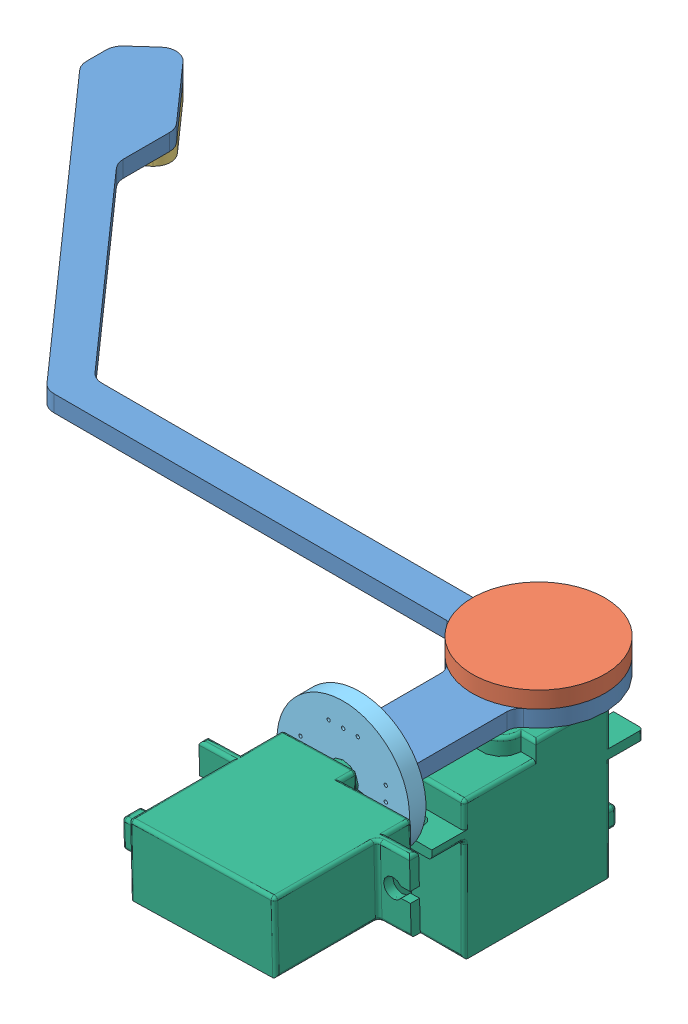
SolidWorks assembly Record Needle Main, configuration Default. Lengths in mm.
Overall size (169.13 48.12 136.87).
8 component instances, 7 part files, 10 mates.
Components (placement in the parent):
- Needle Arm-1: Needle Arm [Default] at origin size (154.66 3.17 103.67)
- X-Y Turn Top-1: X-Y Turn Top [Default] at origin size (25.4 3.17 25.4)
- Needle Bottom-1: Needle Bottom [Default] at origin size (18.51 3.17 20.89)
- Needle Point-1: Needle Point [Default] at (-130.291 -3.175 -53.8527) x (-0.670402 0 -0.741998) z (0 1 0) size (6.35 3.17 9.52)
- X-Z Servo Mount-1: X-Z Servo Mount [Default] at (0 1.5875 37.465) x (0 -1 0) z (1 0 0) size (25.4 3.17 25.4)
- Part4^Record Needle Main-1: Part4^Record Needle Main [Default] at origin (virtual)
- HK15148 Servo-1: HK15148 Servo [Default] at (-6.724 -33.8328 20.774) x (0.999994 0 0.003328) z (-0.003328 0 0.999994) size (13.31 33.83 40.39)
- HK15148 Servo-3: HK15148 Servo [Default] at (20.6314 8.7369 71.2978) x (0.023875 -0.999715 0) z (0.999715 0.023875 0) size (13.31 33.83 40.39)
Mates (geometry in assembly coordinates):
- Coincident3: coincident: line of Needle Bottom-1 through (-134.5481 -3.175 -58.5644) axis (0.670402 0 0.741998); plane of Needle Point-1 through (-130.291 -3.175 -53.8527) normal (0.741998 0 -0.670402)
- Coincident4: coincident anti-aligned: plane of Needle Arm-1 through (0 0 0) normal (0 -1 0); plane of Needle Point-1 through (-132.6469 0 -51.7242) normal (0 1 0)
- Coincident5: coincident anti-aligned: plane of Needle Bottom-1 through (-132.6469 0 -51.7242) normal (-0.670402 0 -0.741998); plane of Needle Point-1 through (-132.6469 -3.175 -51.7242) normal (0.670402 0 0.741998)
- Coincident6: coincident anti-aligned: plane of Needle Arm-1 through (0 3.175 34.29) normal (0 0 1); plane of X-Z Servo Mount-1 through (0 1.5875 34.29) normal (0 0 -1)
- Coincident7: coincident anti-aligned: plane of Needle Arm-1 through (0 0 0) normal (0 -1 0); plane of X-Z Servo Mount-1 through (2.1167 0 37.465) normal (0 1 0)
- Coincident8: coincident anti-aligned: plane of Needle Arm-1 through (-2.1167 3.175 0) normal (-1 0 0); plane of X-Z Servo Mount-1 through (-2.1167 3.175 37.465) normal (1 0 0)
- Coincident9: coincident anti-aligned: plane of X-Z Servo Mount-1 through (0 1.5875 37.465) normal (0 0 1); circle of HK15148 Servo-3
- Concentric1: concentric aligned: circle of X-Z Servo Mount-1; circle of HK15148 Servo-3
- Concentric2: concentric aligned: circle of Needle Arm-1; circle of HK15148 Servo-1
- Coincident10: coincident anti-aligned: plane of Needle Arm-1 through (0 0 0) normal (0 -1 0); plane of HK15148 Servo-1 through (0 0 0) normal (0 1 0)
